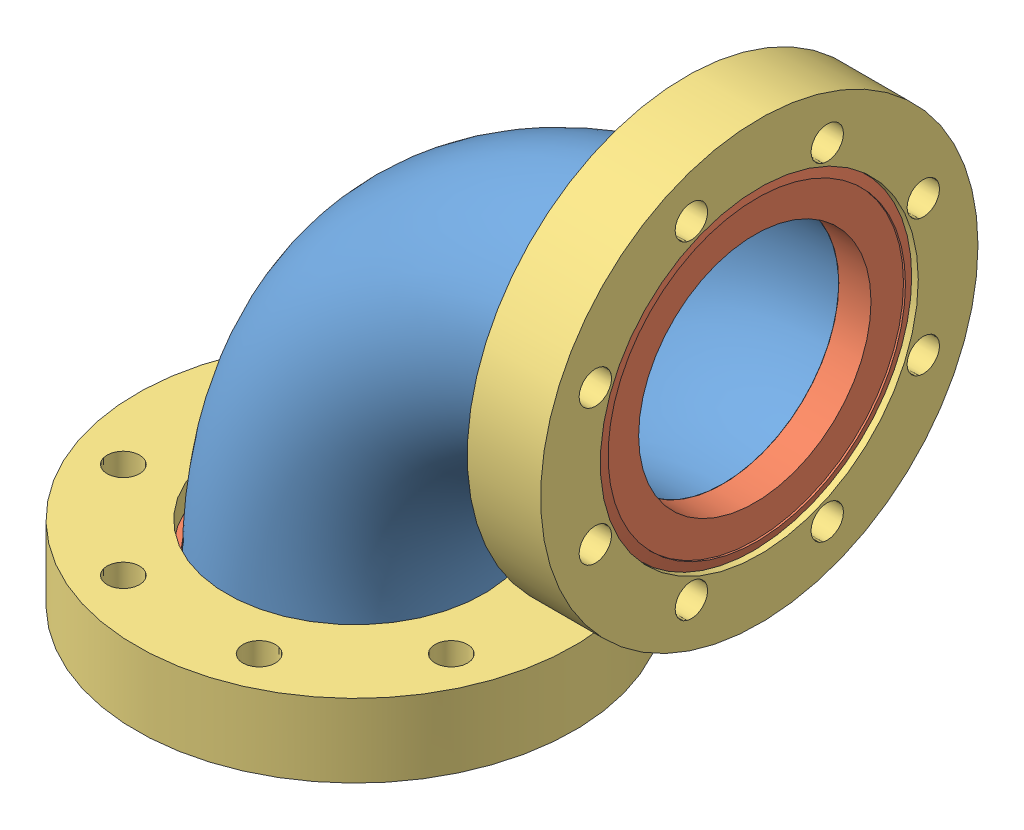
SolidWorks assembly 403004_1, configuration Default. Lengths in mm.
Overall size (161.67 161.67 113.54).
7 component instances, 3 part files, 0 mates.
Components (placement in the parent):
- 403004-001_1-1: 403004-001_1 [Default] at origin size (128.92 128.92 67.08)
- 100021 (4.5 X 2.5 R)_2-1: 100021 (4.5 X 2.5 R)_2 [Default] at (92.202 95.377 0) x (1 0 0) z (0 0 -1) size (19.05 113.54 113.54)
  - 100021 (4.5 X 2.5 INS)_2-1: 100021 (4.5 X 2.5 INS)_2 [Default] at origin size (12.04 82.3 82.3)
  - 100021 (4.5 X 2.5 REC)_2-1: 100021 (4.5 X 2.5 REC)_2 [Default] at (-6.35 0 0) x (1 0 0) z (0 0 -1) size (19.05 113.54 113.54)
- 100021 (4.5 X 2.5 R)_2-2: 100021 (4.5 X 2.5 R)_2 [Default] at (0 3.175 0) x (0 -1 0) z (0 0 -1) size (19.05 113.54 113.54)
  - 100021 (4.5 X 2.5 INS)_2-1: 100021 (4.5 X 2.5 INS)_2 [Default] at origin size (12.04 82.3 82.3)
  - 100021 (4.5 X 2.5 REC)_2-1: 100021 (4.5 X 2.5 REC)_2 [Default] at (-6.35 0 0) x (1 0 0) z (0 0 -1) size (19.05 113.54 113.54)
